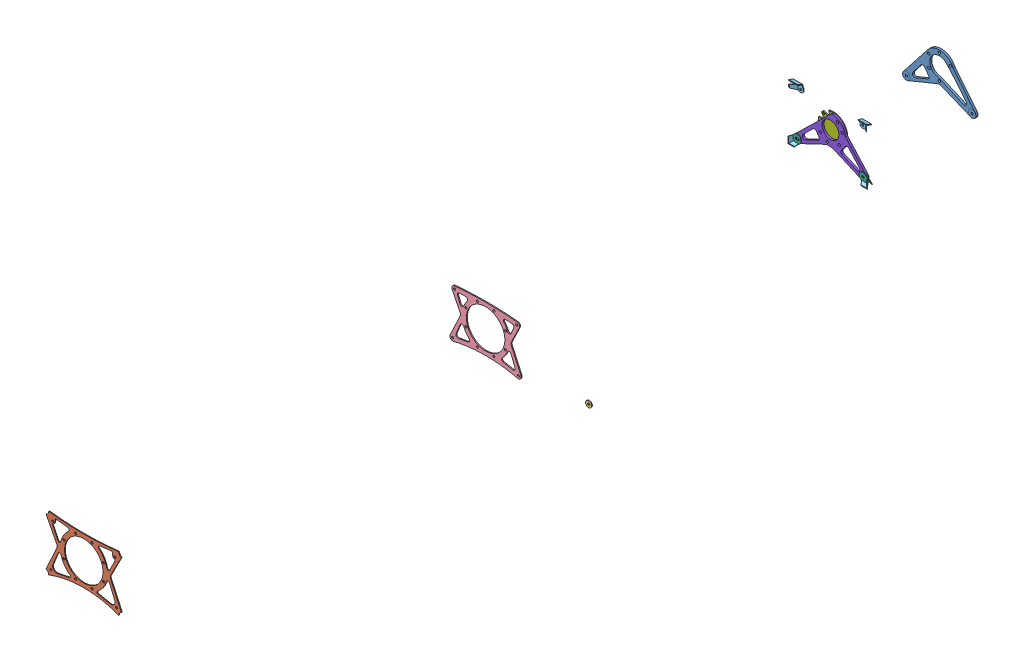
SolidWorks assembly Drivetrain Parts Drawings, configuration Default. Lengths in mm.
Overall size (1609.07 1655.79 7.3).
10 component instances, 10 part files, 6 mates.
Components (placement in the parent):
- Motor Base Sketches-1: Motor Base Sketches [Default] at origin size (1609.07 1655.79 0)
- Motor Offset sketches-1: Motor Offset sketches [Default] at origin size (258.63 213.35 0) (hidden)
- Motor Support Right-1: Motor Support Right [Default] at (97.1444 4.8961 -344.7619) size (232.37 135.39 6.35) (hidden)
- Planetary Inner Support-1: Planetary Inner Support [Default] at (51.7512 -11.4611 2367.4241) x (0.752176 0.658962 0) z (0 0 1) size (281.31 276.88 2.54) (hidden)
- Support Spacers-1: Support Spacers [Default] at (174.8614 -95.5813 929.5339) x (0.752176 0.658962 0) z (0 0 1) size (19.05 19.05 2.54) (hidden)
- Planetary Outer Support-1: Planetary Outer Support [Default] at (-153.7044 112.2497 1094.761) size (229.19 161.54 3.17) (hidden)
- Planetary Outer Support Tabs-1: Planetary Outer Support Tabs [Default] at origin size (252.05 176.53 15.02) (hidden)
- Motor Support Tabs-1: Motor Support Tabs [Default] at origin size (263.82 39.6 2.54)
- Resolver Plate-1: Resolver Plate [Default] x (0 0 -1) z (0.707107 0.707107 0) size (3 90.17 90.17) (hidden)
- Motor Support Left-1: Motor Support Left [Default] at origin size (232.37 134.39 6.35) (hidden)
Mates (geometry in assembly coordinates):
- Concentric1: concentric anti-aligned: circle of Motor Base Sketches-1; cylinder of Motor Support Left-1 through (0 0 6.35) axis (0 0 -1) radius 26.67
- Coincident1: coincident anti-aligned: plane of Motor Support Left-1 through (-104.3764 -76.4776 0) normal (0 0 -1); plane of assembly through (0 0 0) normal (0 0 1)
- Coincident2: coincident aligned: plane of Motor Support Left-1 through (0 0 0) normal (0 1 0); plane of assembly through (0 0 0) normal (0 1 0)
- Coincident3: coincident anti-aligned: plane of Motor Support Left-1 through (-104.3764 -76.4776 0) normal (0 0 -1); plane of Resolver Plate-1 through (0 0 0) normal (0 0 1)
- Concentric2: concentric anti-aligned: cylinder of Motor Support Left-1 through (0 0 6.35) axis (0 0 -1) radius 26.67; cylinder of Resolver Plate-1 through (0 0 -3) axis (0 0 1) radius 45.085
- Concentric5: concentric: point of Motor Support Left-1; cylinder of Resolver Plate-1 through (-27.5772 27.5772 -3) axis (0 0 1) radius 3.4
